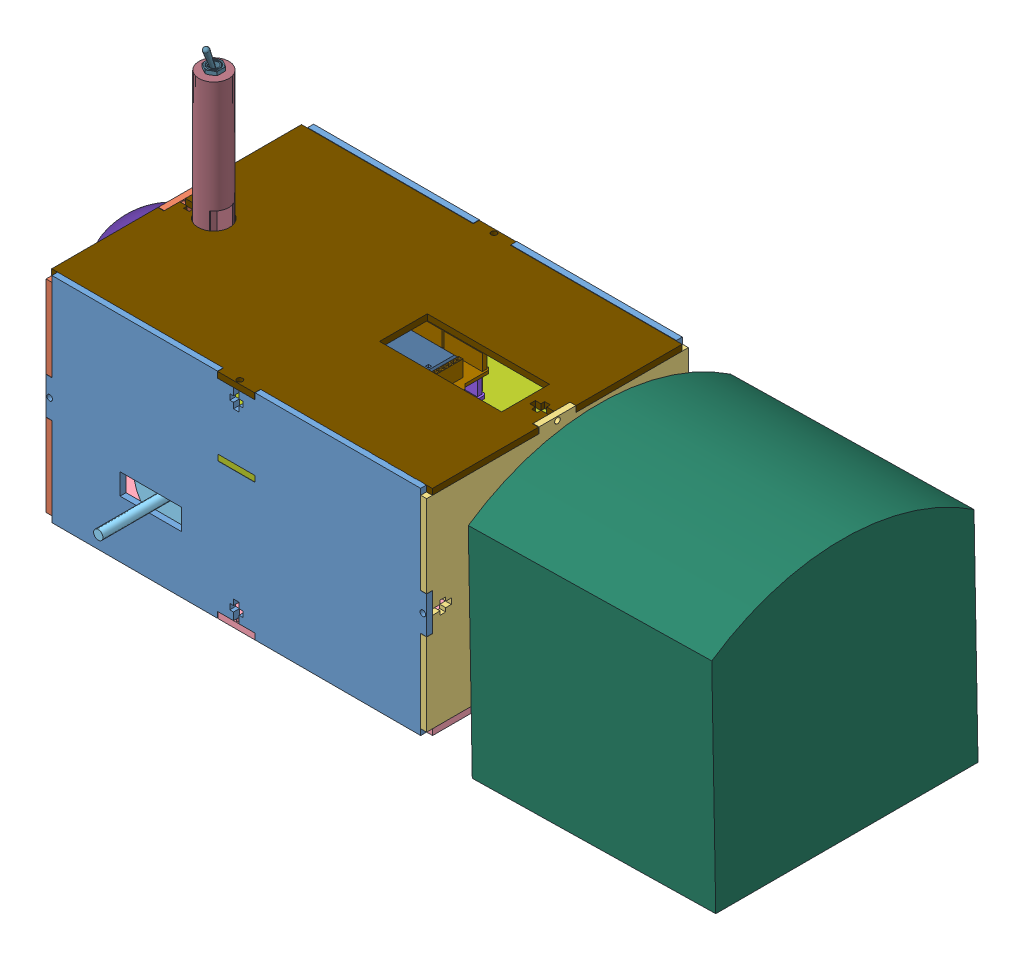
SolidWorks assembly DANKESTTANKEST TRU ASSEMBLY, configuration Default. Lengths in mm.
Overall size (398.95 201.4 178.55).
25 component instances, 19 part files, 51 mates.
Components (placement in the parent):
- Tru Walls DANKTANK-1: Tru Walls DANKTANK [Default] at (98.1865 113.7996 138.9151) size (203.2 114.3 3.18)
- Part2^DANKESTTANKEST TRU ASSEMBLY-1: Part2^DANKESTTANKEST TRU ASSEMBLY [Default] at origin (virtual)
- Tru Walls DANKTANK small-1: Tru Walls DANKTANK small [Default] at (-0.2335 113.6746 208.7651) x (0 1 0) z (-1 0 0) size (114.3 139.7 3.18)
- Tru Walls DANKTANK small face-1: Tru Walls DANKTANK small face [Default] at (199.7865 113.6746 208.7651) x (0 1 0) z (-1 0 0) size (114.3 139.7 3.18)
- Tru Walls DANKTANK bottom-1: Tru Walls DANKTANK bottom [Default] at (98.1865 56.5246 208.7651) x (0 0 -1) z (0 1 0) size (139.7 203.2 3.18)
- motor-1: motor [Default] at (137.2373 91.4546 267.9444) x (0.421788 0.906695 0) z (0 0 -1) size (38.1 38.1 139.7)
- motor-2: motor [Default] at (52.6796 91.4546 167.0951) x (0.369243 0.929333 0) z (0 0 1) size (38.1 38.1 139.7)
- clamp Dank-1: clamp Dank [Default] at (137.2373 76.7173 167.804) size (54.51 60.04 10)
- clamp Dank-2: clamp Dank [Default] at (137.2373 76.7173 239.4593) size (54.51 60.04 10)
- clamp Dank-3: clamp Dank [Default] at (52.6796 76.7173 239.7251) size (54.51 60.04 10)
- clamp Dank-4: clamp Dank [Default] at (52.6796 76.7173 168.7246) size (54.51 60.04 10)
- Tru Walls DANKTANK-3: Tru Walls DANKTANK [Default] at (98.1865 113.6746 278.6151) x (-1 0 0) z (0 0 -1) size (203.2 114.3 3.18)
- Tru Walls DANKTANK bottomtmid-1: Tru Walls DANKTANK bottomtmid [Default] at (98.1865 129.486 208.7651) x (0 0 -1) z (0 1 0) size (139.7 200.02 3.18)
- ArduinoUno-1: ArduinoUno [Default] at (101.022 132.666 207.6097) x (0.999999 0 0.001597) z (-0.001597 0 0.999999) size (74.8 12.1 53.3)
- Prototyping Shield-Simple-1: Prototyping Shield-Simple [Default] at (120.7047 107.9998 262.0246) x (-0.999999 0 -0.001597) z (0.001597 0 -0.999999) size (68 18.92 56)
  - Arduino Prototyping Shield-1: Arduino Prototyping Shield [Default] at (18.3696 35.0162 55.7334) size (68 18.92 56)
  - MiniBreadboard-Simple-1: MiniBreadboard-Simple [Default] at (16.6696 36.6462 55.7334) x (0 0 1) z (-1 0 0) size (34.6 8.15 45.6)
- back wall tank-1: back wall tank [Default] at (-0.2335 116.1725 202.5739) x (0 0 1) z (-1 0 0) size (12.27 23 3.18)
- HC-SR04 WITH CONFIGURATIONS-1: HC-SR04 WITH CONFIGURATIONS [With Oscillator] at (1.4665 142.916 208.7651) x (0 0 1) z (-1 0 0) size (45.2 26.75 18.52)
- cho cho slank damnk-1: cho cho slank damnk [Default] at (16.3891 239.266 208.7651) x (1 0 0) z (0 -1 0) size (18.52 47.93 106.6)
- Panel Mount SPDT-2: Panel Mount SPDT [Default] at (16.5378 224.3497 208.9589) size (8 31.74 12.7)
- THOMAS THE DANK TANK-1: THOMAS THE DANK TANK [Default] at (343.1785 113.0415 208.7651) x (0 0 1) z (-0.999832 -0.018349 0) size (140 136.9 130)
- Battery scank dank-1: Battery scank dank [Default] at (285.728 109.8218 208.7651) x (0 0 -1) z (0.018349 -0.999832 0) size (49.99 115 48)
- FACE DANAKKKKKKKKKKKKKKKK SO MADDDDD-2: FACE DANAKKKKKKKKKKKKKKKK SO MADDDDD [Default] at (9.7732 125.1372 208.7651) x (0 0 1) z (-1 0 0) size (68.15 68.15 54.44)
- Tru Walls DANKTANK butt-1: Tru Walls DANKTANK butt [Default] at (98.1865 170.8246 208.8901) x (0 0 -1) z (0 -1 0) size (139.7 203.2 3.18)
Mates (geometry in assembly coordinates):
- Coincident10: coincident aligned: plane of Tru Walls DANKTANK small-1 through (-0.2335 113.6746 208.7651) normal (0 0 -1); plane of Tru Walls DANKTANK bottom-1 through (98.1865 56.5246 208.7651) normal (0 0 -1)
- Coincident11: coincident anti-aligned: plane of Tru Walls DANKTANK small-1 through (-0.2335 113.6746 208.7651) normal (1 0 0); plane of Tru Walls DANKTANK bottom-1 through (-0.2335 56.5246 207.2651) normal (-1 0 0)
- Parallel2: parallel anti-aligned: plane of Tru Walls DANKTANK-1 through (98.1865 113.7996 142.0951) normal (0 0 1); plane of motor-2 through (52.6796 91.4546 167.0951) normal (0 0 -1)
- Distance2: distance = 25 mm anti-aligned: plane of motor-2 through (52.6796 91.4546 167.0951) normal (0 0 -1); plane of Tru Walls DANKTANK-1 through (98.1865 113.7996 142.0951) normal (0 0 1)
- Distance3: distance = 12.7 mm anti-aligned: cylinder of motor-1 through (137.2373 91.4546 166.3444) axis (0 0 1) radius 19.05; plane of Tru Walls DANKTANK bottom-1 through (98.1865 59.7046 208.7651) normal (0 1 0)
- Distance4: distance = 12.7 mm anti-aligned: cylinder of motor-2 through (52.6796 91.4546 268.6951) axis (0 0 -1) radius 19.05; plane of Tru Walls DANKTANK bottom-1 through (98.1865 59.7046 208.7651) normal (0 1 0)
- Concentric1: concentric aligned: cylinder of motor-1 through (137.2373 91.4546 166.3444) axis (0 0 1) radius 19.05; cylinder of clamp Dank-1 through (137.2373 91.4546 167.804) axis (0 0 1) radius 19.075
- Parallel3: parallel anti-aligned: plane of Tru Walls DANKTANK bottom-1 through (98.1865 59.7046 208.7651) normal (0 1 0); plane of clamp Dank-1 through (151.6382 59.6736 177.804) normal (0 -1 0)
- Concentric2: concentric aligned: cylinder of motor-1 through (137.2373 91.4546 166.3444) axis (0 0 1) radius 19.05; cylinder of clamp Dank-2 through (137.2373 91.4546 239.4593) axis (0 0 1) radius 19.075
- Concentric3: concentric anti-aligned: cylinder of motor-2 through (52.6796 91.4546 268.6951) axis (0 0 -1) radius 19.05; cylinder of clamp Dank-4 through (52.6796 91.4546 168.7246) axis (0 0 1) radius 19.075
- Parallel5: parallel anti-aligned: plane of Tru Walls DANKTANK bottom-1 through (98.1865 59.7046 208.7651) normal (0 1 0); plane of clamp Dank-4 through (67.0806 59.6736 178.7246) normal (0 -1 0)
- Parallel7: parallel anti-aligned: plane of clamp Dank-1 through (122.8363 59.6736 177.804) normal (-1 0 0); plane of clamp Dank-4 through (67.0806 59.6736 178.7246) normal (1 0 0)
- Concentric4: concentric anti-aligned: cylinder of motor-2 through (52.6796 91.4546 268.6951) axis (0 0 -1) radius 19.05; cylinder of clamp Dank-3 through (52.6796 91.4546 239.7251) axis (0 0 1) radius 19.075
- Parallel8: parallel anti-aligned: plane of Tru Walls DANKTANK bottom-1 through (98.1865 59.7046 208.7651) normal (0 1 0); plane of clamp Dank-3 through (67.0806 59.6736 249.7251) normal (0 -1 0)
- Parallel9: parallel anti-aligned: plane of clamp Dank-2 through (122.8363 59.6736 249.4593) normal (-1 0 0); plane of clamp Dank-3 through (67.0806 59.6736 249.7251) normal (1 0 0)
- Coincident26: coincident aligned: line of Tru Walls DANKTANK small face-1 through (199.7865 123.6746 275.4351) axis (0 -1 0); line of Tru Walls DANKTANK-3 through (199.7865 123.5496 275.4351) axis (0 -1 0)
- Coincident29: coincident aligned: line of Tru Walls DANKTANK small face-1 through (196.6065 56.5246 198.8901) axis (0 0 1); line of Tru Walls DANKTANK bottom-1 through (196.6065 56.5246 198.7651) axis (0 0 1)
- Coincident30: coincident anti-aligned: plane of Tru Walls DANKTANK-1 through (98.1865 113.7996 142.0951) normal (0 0 1); plane of Tru Walls DANKTANK small face-1 through (199.7865 103.6746 142.0951) normal (0 0 -1)
- Coincident32: coincident anti-aligned: line of Tru Walls DANKTANK small-1 through (-0.2335 56.5246 198.8901) axis (0 0 1); line of Tru Walls DANKTANK bottom-1 through (-0.2335 56.5246 207.2651) axis (0 0 -1)
- Coincident33: coincident aligned: line of Tru Walls DANKTANK-1 through (199.7865 103.9246 142.0951) axis (0 1 0); line of Tru Walls DANKTANK small face-1 through (199.7865 115.1746 142.0951) axis (0 1 0)
- Coincident34: coincident anti-aligned: line of Tru Walls DANKTANK-1 through (199.7865 123.6746 138.9151) axis (0 0 1); line of Tru Walls DANKTANK small face-1 through (199.7865 123.6746 142.0951) axis (0 0 -1)
- Parallel10: parallel aligned: line of Tru Walls DANKTANK-1 through (108.1865 59.8296 138.9151) axis (-1 0 0); line of Tru Walls DANKTANK bottom-1 through (108.0615 59.7046 138.9151) axis (-1 0 0)
- Coincident36: coincident anti-aligned: line of Tru Walls DANKTANK-1 through (-3.4135 123.6746 142.0951) axis (0 -1 0); line of Tru Walls DANKTANK small-1 through (-3.4135 115.1746 142.0951) axis (0 1 0)
- Coincident37: coincident aligned: line of Tru Walls DANKTANK bottom-1 through (88.3115 59.7046 278.6151) axis (1 0 0); line of Tru Walls DANKTANK-3 through (99.6865 59.7046 278.6151) axis (1 0 0)
- Coincident40: coincident aligned: plane of Tru Walls DANKTANK bottom-1 through (98.1865 56.5246 208.7651) normal (0 0 -1); plane of Tru Walls DANKTANK bottomtmid-1 through (98.1865 129.486 208.7651) normal (0 0 -1)
- Parallel11: parallel anti-aligned: plane of Tru Walls DANKTANK bottom-1 through (98.1865 59.7046 208.7651) normal (0 1 0); plane of Tru Walls DANKTANK bottomtmid-1 through (98.1865 129.486 208.7651) normal (0 -1 0)
- Coincident42: coincident aligned: plane of Tru Walls DANKTANK bottom-1 through (98.1865 56.5246 208.7651) normal (-1 0 0); plane of Tru Walls DANKTANK bottomtmid-1 through (98.1865 129.486 208.7651) normal (-1 0 0)
- Coincident47: coincident anti-aligned: plane of Tru Walls DANKTANK bottomtmid-1 through (98.1865 132.666 208.7651) normal (0 1 0); plane of ArduinoUno-1 through (134.0645 132.666 181.0125) normal (0 -1 0)
- Coincident48: coincident anti-aligned: plane of ArduinoUno-1 through (134.0645 134.266 181.0125) normal (0 1 0); plane of Prototyping Shield-Simple-1/Arduino Prototyping Shield-1 through (131.0545 134.266 181.0076) normal (0 -1 0)
- Concentric9: concentric aligned: circle of ArduinoUno-1; circle of Prototyping Shield-Simple-1/Arduino Prototyping Shield-1
- Coincident50: coincident aligned: line of Tru Walls DANKTANK-1 through (108.0615 129.486 138.9151) axis (-1 0 0); line of Tru Walls DANKTANK bottomtmid-1 through (108.0615 129.486 138.9151) axis (-1 0 0)
- Parallel14: parallel aligned: line of ArduinoUno-1 through (133.0645 134.266 181.0109) axis (-0.999999 0 -0.001597); line of Prototyping Shield-Simple-1/Arduino Prototyping Shield-1 through (132.6088 144.646 178.3101) axis (-0.999999 0 -0.001597)
- Concentric13: concentric anti-aligned: cylinder of Tru Walls DANKTANK bottom-1 through (146.1499 59.7046 173.0938) axis (0 -1 0) radius 1.59; cylinder of clamp Dank-1 through (146.1499 52.8536 173.0938) axis (0 1 0) radius 1.59
- Concentric14: concentric anti-aligned: cylinder of Tru Walls DANKTANK bottom-1 through (61.5923 59.7046 174.0144) axis (0 -1 0) radius 1.59; cylinder of clamp Dank-4 through (61.5923 52.8536 174.0144) axis (0 1 0) radius 1.59
- Parallel16: parallel anti-aligned: plane of Tru Walls DANKTANK small face-1 through (196.6065 113.6746 208.7651) normal (-1 0 0); plane of back wall tank-1 through (-0.2335 116.1725 202.5739) normal (1 0 0)
- Coincident55: coincident anti-aligned: plane of Tru Walls DANKTANK small-1 through (-12.2335 65.1035 254.1276) normal (0 1 0); plane of back wall tank-1 through (-0.2335 65.1035 254.1276) normal (0 -1 0)
- Coincident56: coincident anti-aligned: line of Tru Walls DANKTANK small-1 through (-3.4135 68.1035 246.6276) axis (0 1 0); line of back wall tank-1 through (-3.4135 82.1035 246.6276) axis (0 -1 0)
- Parallel18: parallel anti-aligned: plane of Tru Walls DANKTANK small face-1 through (196.6065 113.6746 208.7651) normal (-1 0 0); plane of HC-SR04 WITH CONFIGURATIONS-1 through (1.4665 142.916 208.7651) normal (1 0 0)
- Coincident58: coincident anti-aligned: line of Tru Walls DANKTANK bottomtmid-1 through (-0.2335 132.666 275.4351) axis (0 0 -1); line of HC-SR04 WITH CONFIGURATIONS-1 through (-0.2335 132.666 186.1651) axis (0 0 1)
- Coincident59: coincident anti-aligned: plane of Tru Walls DANKTANK small-1 through (-0.2335 113.6746 208.7651) normal (0 0 -1); plane of HC-SR04 WITH CONFIGURATIONS-1 through (1.4665 142.916 208.7651) normal (0 0 1)
- Coincident60: coincident anti-aligned: plane of Tru Walls DANKTANK bottomtmid-1 through (98.1865 132.666 208.7651) normal (0 1 0); plane of cho cho slank damnk-1 through (16.3891 132.666 208.7651) normal (0 -1 0)
- Parallel19: parallel anti-aligned: plane of Tru Walls DANKTANK small face-1 through (196.6065 113.6746 208.7651) normal (-1 0 0); plane of cho cho slank damnk-1 through (25.6489 132.666 184.8014) normal (1 0 0)
- Coincident62: coincident anti-aligned: plane of Tru Walls DANKTANK bottom-1 through (98.1865 56.5246 208.7651) normal (0 0 -1); plane of cho cho slank damnk-1 through (16.3891 239.266 208.7651) normal (0 0 1)
- Coincident63: coincident anti-aligned: plane of Tru Walls DANKTANK bottom-1 through (98.1865 56.5246 208.7651) normal (0 0 -1); plane of THOMAS THE DANK TANK-1 through (343.1785 113.0415 208.7651) normal (0 0 1)
- Coincident64: coincident anti-aligned: plane of THOMAS THE DANK TANK-1 through (343.1785 113.0415 208.7651) normal (0 0 1); plane of Battery scank dank-1 through (285.728 109.8218 208.7651) normal (0 0 -1)
- Coincident65: coincident anti-aligned: plane of THOMAS THE DANK TANK-1 through (344.099 62.8849 208.7651) normal (-0.999832 -0.018349 0); plane of Battery scank dank-1 through (344.099 62.8849 233.7588) normal (0.999832 0.018349 0)
- Coincident66: coincident anti-aligned: plane of THOMAS THE DANK TANK-1 through (224.1192 60.6831 268.7651) normal (-0.018349 0.999832 0); plane of Battery scank dank-1 through (286.6087 61.8299 208.7651) normal (0.018349 -0.999832 0)
- Concentric15: concentric anti-aligned: cylinder of Tru Walls DANKTANK small-1 through (6.5865 125.1372 208.7651) axis (-1 0 0) radius 32.6714; cylinder of FACE DANAKKKKKKKKKKKKKKKK SO MADDDDD-2 through (-40.2268 125.1372 208.7651) axis (1 0 0) radius 34.075
- Coincident67: coincident anti-aligned: plane of Tru Walls DANKTANK small-1 through (-0.2335 113.6746 208.7651) normal (0 0 -1); plane of FACE DANAKKKKKKKKKKKKKKKK SO MADDDDD-2 through (9.7732 125.1372 208.7651) normal (0 0 1)
- Coincident69: coincident anti-aligned: line of Tru Walls DANKTANK small-1 through (-0.2335 170.8246 218.6401) axis (0 0 -1); line of Tru Walls DANKTANK butt-1 through (-0.2335 170.8246 198.8901) axis (0 0 1)
- Coincident70: coincident anti-aligned: line of Tru Walls DANKTANK small-1 through (-3.4135 167.6446 198.8901) axis (0 1 0); line of Tru Walls DANKTANK butt-1 through (-3.4135 170.8246 198.8901) axis (0 -1 0)
